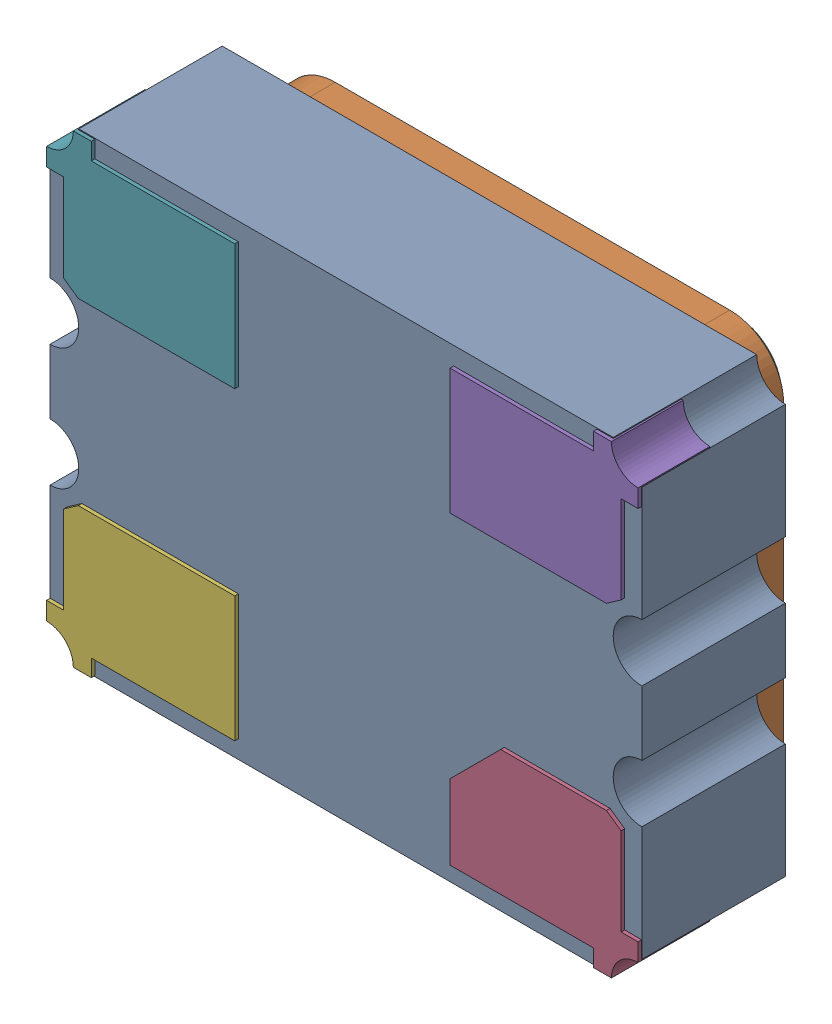
SolidWorks assembly Y2K60, configuration 默认. Lengths in mm.
Overall size (3.3 2.6 1.1).
5 component instances, 4 part files, 0 mates.
Components (placement in the parent):
- XTAL-OSC-3225-1: XTAL-OSC-3225 [默认] at (-24.3585 3.8353 -0.3912) x (1 0 0) z (0 0 -1) size (3.3 2.6 1.1)
  - User_Library-ASTX-H11_Pad-1: User_Library-ASTX-H11_Pad [默认] at origin size (3.3 2.6 0.8)
  - User_Library-ASTX-H11_Pad001-1: User_Library-ASTX-H11_Pad001 [默认] at origin size (2.8 2.4 0.24)
  - User_Library-ASTX-H11_Pad002-1: User_Library-ASTX-H11_Pad002 [默认] at origin size (2.7 2.3 0.04)
  - User_Library-ASTX-H11_ComponentPads-1: User_Library-ASTX-H11_ComponentPads [默认] at origin size (3.3 2.59 0.4)
